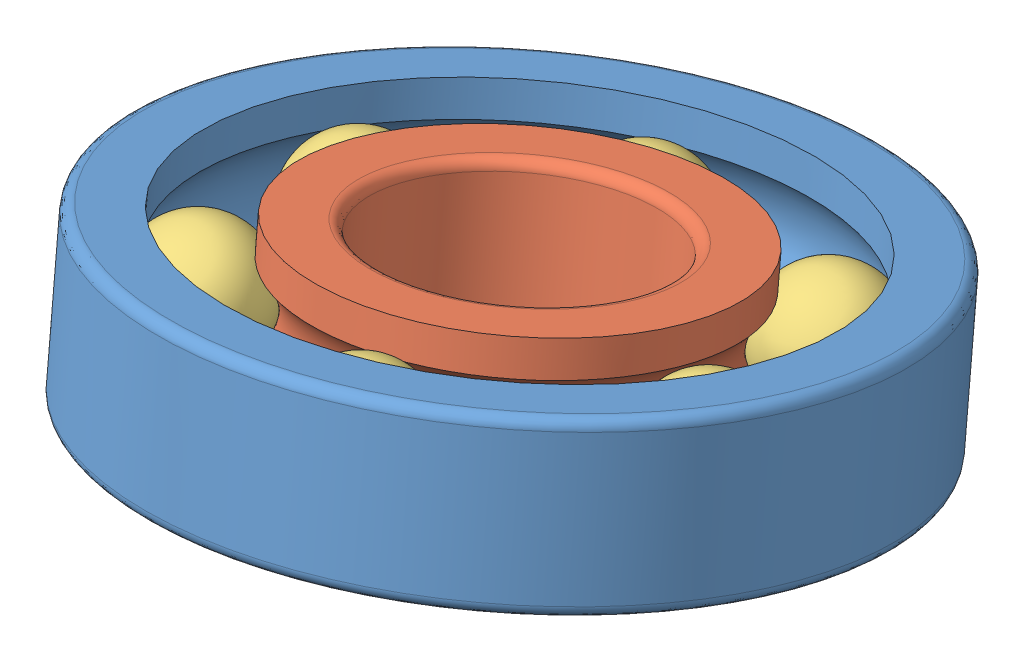
SolidWorks assembly Bearing, configuration Default. Lengths in mm.
Overall size (160.37 61.99 162.8).
8 component instances, 3 part files, 8 mates.
Components (placement in the parent):
- Outer_Ring-1: Outer_Ring [Default] at (-20.3519 222.2008 -42.9464) x (-0.089567 0.977883 -0.189003) z (0.247512 0.205666 0.946805) size (31 130 130)
- Inner_Ring-1: Inner_Ring [Default] at (-20.3519 222.2008 -42.9464) x (-0.089567 0.977883 -0.189003) z (0.247512 0.205666 0.946805) size (31 74 74)
- Bearing_Ball-1: Bearing_Ball [Default] at (-8.2616 231.4912 -0.6084) x (-0.588764 -0.777319 0.221656) z (0.792046 -0.60953 -0.033705) size (24 24 24)
- Bearing_Ball-2: Bearing_Ball [Default] at (-35.564 212.8252 -84.2464) x (-0.404113 -0.885641 -0.228766) z (0.90926 -0.361682 -0.205991) size (24 24 24)
- Bearing_Ball-3: Bearing_Ball [Default] at (-56.8492 223.9347 -16.6797) x (-0.588764 -0.777319 0.221656) z (0.792046 -0.60953 -0.033705) size (24 24 24)
- Bearing_Ball-4: Bearing_Ball [Default] at (-63.255 215.9426 -54.9946) x (0.174157 -0.772182 0.611069) z (0.984093 0.114384 -0.135928) size (24 24 24)
- Bearing_Ball-5: Bearing_Ball [Default] at (8.7677 218.2804 -77.0299) x (-0.973347 -0.219892 0.065142) z (0.108434 -0.190967 0.975589) size (24 24 24)
- Bearing_Ball-6: Bearing_Ball [Default] at (23.8637 226.3274 -37.8926) x (-0.341406 -0.939363 -0.032247) z (0.936774 -0.337261 -0.093327) size (24 24 24)
Mates (geometry in assembly coordinates):
- Concentric1: concentric aligned: circle of Outer_Ring-1; circle of Inner_Ring-1
- Coincident2: coincident aligned: plane of Outer_Ring-1 through (-84.448 234.8866 -28.9462) normal (-0.089567 0.977883 -0.189003); plane of Inner_Ring-1 through (-47.7881 236.3314 -38.8436) normal (-0.089567 0.977883 -0.189003)
- Tangent1: tangent anti-aligned: torus of Inner_Ring-1; sphere of Bearing_Ball-1
- Tangent3: tangent anti-aligned: torus of Inner_Ring-1; sphere of Bearing_Ball-2
- Concentric4: concentric: cylinder of Inner_Ring-1 through (-18.9636 207.0436 -40.0169) axis (0.089567 -0.977883 0.189003) radius 25
- Tangent4: tangent anti-aligned: torus of Inner_Ring-1; sphere of Bearing_Ball-3
- Tangent5: tangent anti-aligned: torus of Inner_Ring-1; sphere of Bearing_Ball-4
- Tangent6: tangent anti-aligned: torus of Inner_Ring-1; sphere of Bearing_Ball-5
